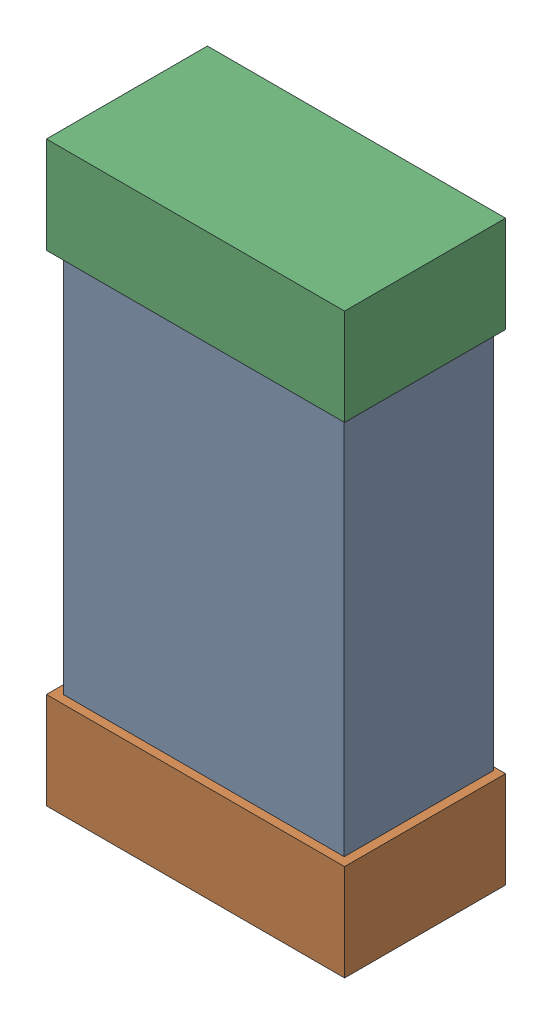
SolidWorks assembly C25, configuration Default. Lengths in mm.
Overall size (0.85 1.65 0.46).
6 component instances, 2 part files, 0 mates.
Components (placement in the parent):
- 432124816_35-1: 432124816_35 [Default] at (11.2251 19.4533 -0.8615) size (0.8 1.5 0.42)
  - Extruded (1)-1: Extruded (1) [Default] at origin size (0.8 1.5 0.42)
- 432138512_70-1: 432138512_70 [Default] at (11.2251 18.7675 -0.8715) size (0.85 0.28 0.46)
  - Extruded-1: Extruded [Default] at origin size (0.85 0.28 0.46)
- 432138512_71-1: 432138512_71 [Default] at (11.2251 20.1391 -0.8715) size (0.85 0.28 0.46)
  - Extruded-1: Extruded [Default] at origin size (0.85 0.28 0.46)
